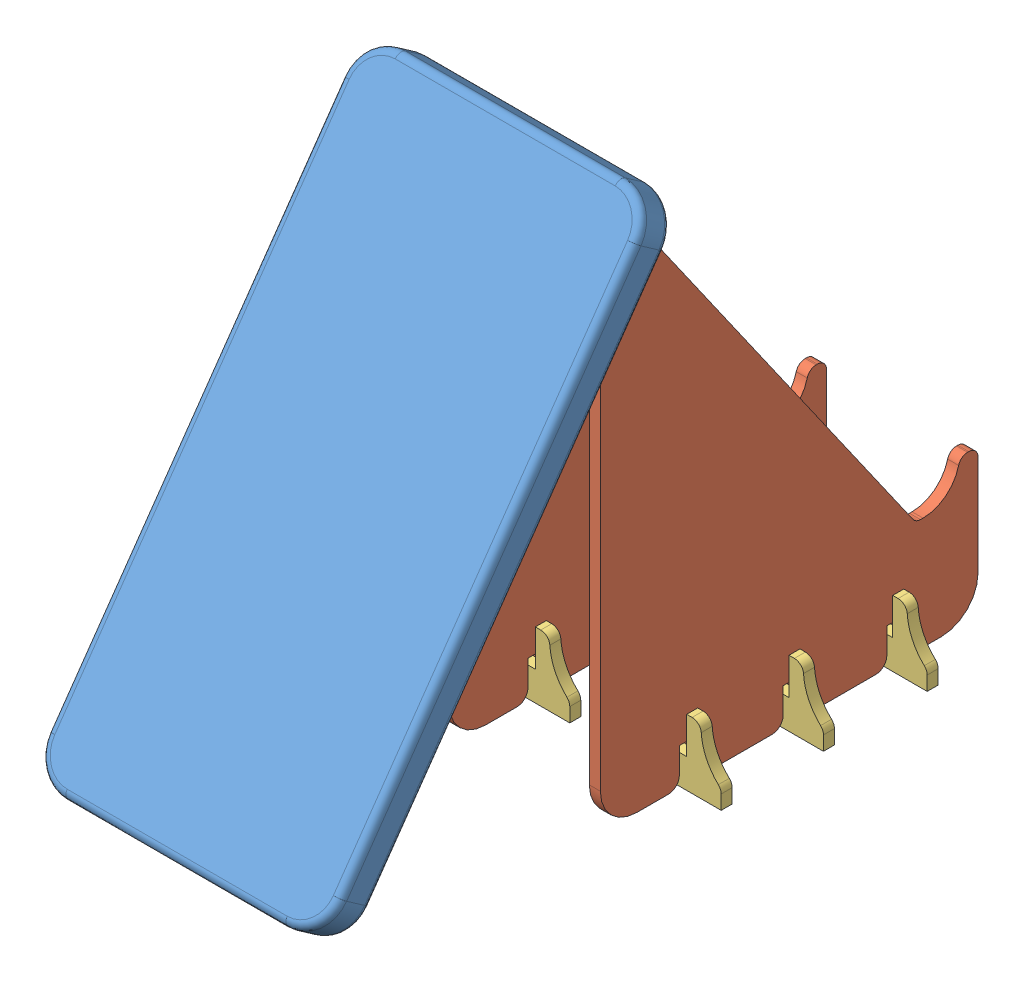
SolidWorks assembly paye mobile, configuration Default. Lengths in mm.
Overall size (80 162.83 199.81).
12 component instances, 5 part files, 35 mates.
Components (placement in the parent):
- iphone7plus-2: iphone7plus [Default] at (-40 -64.385 52.4393) x (-1 0 0) z (0 -0.573576 -0.819152) size (80 160 10)
- Part4-1: Part4 [Default] at origin
- Part5-1: Part5 [Default] at (0 -64.385 52.4393) x (0 -0.573576 -0.819152) z (1 0 0)
- Part6-1: Part6 [Default] x (0 0 -1) z (1 0 0) size (103.02 147.95 3) (hidden)
- Part6-2: Part6 [Default] at (-64.5031 0 0) x (0 0 -1) z (1 0 0) size (103.02 147.95 3)
- Part7-2: Part7 [Default] at (-64.2031 20 -48.3217) x (-1 0 0) z (0 0 -1) size (23.4 17.99 3)
- Part7-3: Part7 [Default] at (-64.2031 20 -76.6217) x (-1 0 0) z (0 0 -1) size (23.4 17.99 3)
- Part6-3: Part6 [Default] at (-23.2051 0 0) x (0 0 -1) z (1 0 0) size (103.02 147.95 3)
- Part7-4: Part7 [Default] at (-22.9051 20 -76.6217) x (-1 0 0) z (0 0 -1) size (23.4 17.99 3)
- Part7-5: Part7 [Default] at (-22.9051 20 -48.3217) x (-1 0 0) z (0 0 -1) size (23.4 17.99 3)
- Part7-6: Part7 [Default] at (-22.9051 20 -20.4254) x (-1 0 0) z (0 0 -1) size (23.4 17.99 3)
- Part7-7: Part7 [Default] at (-64.2031 20 -20.4254) x (-1 0 0) z (0 0 -1) size (23.4 17.99 3)
Mates (geometry in assembly coordinates):
- Angle2: planar angle = 0.610865 rad: plane of assembly through (0 0 0) normal (0 0 1); plane of assembly; plane of iphone7plus-2 through (-70 -121.7257 92.5897) normal (0 0.573576 0.819152)
- Coincident6: coincident: line of assembly; line of iphone7plus-2 through (-70 0 4.9149) axis (1 0 0); plane of assembly
- Coincident7: coincident: plane of assembly through (0 0 0) normal (1 0 0); plane of iphone7plus-2 through (0 -12.7801 4.0975) normal (1 0 0); plane of assembly
- Coincident8: coincident: line of assembly; line of iphone7plus-2 through (-10 -3.4415 0) axis (-1 0 0); plane of assembly
- InPlace2: in place: plane of iphone7plus-2 through (0 -12.7801 4.0975) normal (1 0 0); plane of Part6-1 through (0 0 0) normal (1 0 0); moOrthogonalPlaneRef_w of iphone7plus-2 through (0 -12.7801 4.0975) normal (1 0 0); plane of Part6-1 through (0 0 0) normal (0 1 0); plane of iphone7plus-2 through (0 -12.7801 4.0975) normal (1 0 0); plane of Part6-1 through (0 0 0) normal (0 0 -1); plane of iphone7plus-2 through (0 -12.7801 4.0975) normal (1 0 0); unknown of Part5-1
- Coincident9: coincident: plane of assembly; plane of assembly; plane of iphone7plus-2; plane of Part5-1
- Coincident10: coincident: plane of assembly; plane of assembly; moOrthogonalPlaneRef_w of iphone7plus-2 through (0 -64.385 52.4393) normal (0 0.819152 -0.573576); plane of Part5-1 through (0 -64.385 52.4393) normal (0 0.819152 -0.573576)
- Coincident11: coincident: plane of assembly; plane of assembly; moOrthogonalPlaneRef_w of iphone7plus-2 through (0 -64.385 52.4393) normal (0 0.573576 0.819152); plane of Part5-1 through (0 -64.385 52.4393) normal (0 -0.573576 -0.819152)
- InPlace3: in place: plane of Part6-1 through (0 0 0) normal (1 0 0); plane of Part6-1 through (0 0 0) normal (0 1 0); plane of Part6-1 through (0 0 0) normal (0 0 -1); unknown of Part6-1
- Coincident12: coincident: plane of assembly; plane of Part6-1; plane of assembly
- Coincident13: coincident: plane of assembly; plane of Part6-1 through (0 0 0) normal (0 1 0); moOrthogonalPlaneRef_w of assembly
- Coincident14: coincident: plane of assembly; plane of Part6-1 through (0 0 0) normal (0 0 -1); moOrthogonalPlaneRef_w of assembly
- Coincident16: coincident: plane of assembly; plane of assembly; plane of Part6-1 through (3 -151.6843 1.5402) normal (0 0 1); plane of Part6-2 through (-61.5031 -151.6843 1.5402) normal (0 0 1)
- Coincident17: coincident: line of assembly; plane of assembly; line of Part6-1 through (3 -161.6843 -8.4598) axis (0 0 -1); plane of Part6-2 through (-61.5031 -161.6843 -91.4835) normal (0 -1 0)
- Distance1: distance = 15.4969 mm: plane of assembly; plane of assembly; plane of iphone7plus-2 through (-80 -12.7801 4.0975) normal (-1 0 0); plane of Part6-2 through (-64.5031 -128.6793 -85.7977) normal (-1 0 0)
- Coincident22: coincident: plane of assembly; plane of assembly; plane of Part6-2 through (-61.5031 -161.6843 -48.3217) normal (0 0 -1); plane of Part7-2 through (-58.4355 -146.1943 -48.3217) normal (0 0 1)
- Coincident26: coincident: plane of assembly; plane of assembly; plane of Part7-2 through (-73.9031 -161.6843 -51.3217) normal (-1 0 0); plane of Part7-3 through (-73.9031 -161.6843 -79.6217) normal (-1 0 0)
- Coincident27: coincident: plane of assembly; plane of assembly; plane of Part7-2 through (-63.9031 -161.6843 -51.3217) normal (0 -1 0); plane of Part7-3 through (-63.9031 -161.6843 -79.6217) normal (0 -1 0)
- Coincident28: coincident: plane of assembly; plane of assembly; plane of Part6-2 through (-61.5031 -161.6843 -76.6217) normal (0 0 -1); plane of Part7-3 through (-58.4355 -146.1943 -76.6217) normal (0 0 1)
- Coincident29: coincident: plane of assembly; plane of assembly; plane of Part6-2 through (-61.5031 -124.1843 -101.4835) normal (0 0 -1); plane of Part6-3 through (-20.2051 -124.1843 -101.4835) normal (0 0 -1)
- Coincident30: coincident: plane of assembly; plane of assembly; plane of Part6-2 through (-61.5031 -161.6843 -91.4835) normal (0 -1 0); plane of Part6-3 through (-20.2051 -161.6843 -91.4835) normal (0 -1 0)
- Distance2: distance = 38.298 mm: plane of assembly; plane of assembly; plane of Part6-2 through (-61.5031 -128.6793 -85.7977) normal (1 0 0); plane of Part6-3 through (-23.2051 -128.6793 -85.7977) normal (-1 0 0)
- Coincident32: coincident: plane of assembly; plane of assembly; plane of Part7-3 through (-58.4355 -146.1943 -79.6217) normal (0 0 -1); plane of Part7-4 through (-17.1375 -146.1943 -79.6217) normal (0 0 -1)
- Coincident33: coincident: plane of assembly; plane of assembly; plane of Part7-3 through (-63.9031 -161.6843 -79.6217) normal (0 -1 0); plane of Part7-4 through (-22.6051 -161.6843 -79.6217) normal (0 -1 0)
- Coincident34: coincident: plane of assembly; plane of assembly; plane of Part6-3 through (-23.2051 -128.6793 -85.7977) normal (-1 0 0); plane of Part7-4 through (-23.2051 -143.6943 -79.6217) normal (1 0 0)
- Coincident35: coincident: plane of assembly; plane of assembly; plane of Part7-4 through (-22.6051 -161.6843 -79.6217) normal (0 -1 0); plane of Part7-5 through (-22.6051 -161.6843 -51.3217) normal (0 -1 0)
- Coincident36: coincident: plane of assembly; plane of assembly; plane of Part7-4 through (-9.2051 -161.6843 -79.6217) normal (1 0 0); plane of Part7-5 through (-9.2051 -161.6843 -51.3217) normal (1 0 0)
- Coincident37: coincident: plane of assembly; plane of assembly; plane of Part7-2 through (-58.4355 -146.1943 -51.3217) normal (0 0 -1); plane of Part7-5 through (-17.1375 -146.1943 -51.3217) normal (0 0 -1)
- Coincident39: coincident: plane of assembly; plane of assembly; plane of Part6-3 through (-20.2051 -161.6843 -91.4835) normal (0 -1 0); plane of Part7-6 through (-22.6051 -161.6843 -23.4254) normal (0 -1 0)
- Coincident41: coincident: plane of assembly; plane of assembly; plane of Part7-5 through (-9.2051 -161.6843 -51.3217) normal (1 0 0); plane of Part7-6 through (-9.2051 -161.6843 -23.4254) normal (1 0 0)
- Coincident42: coincident: plane of assembly; plane of assembly; plane of Part7-2 through (-73.9031 -161.6843 -51.3217) normal (-1 0 0); plane of Part7-7 through (-73.9031 -161.6843 -23.4254) normal (-1 0 0)
- Coincident43: coincident: plane of assembly; plane of assembly; plane of Part7-6 through (-22.6051 -161.6843 -23.4254) normal (0 -1 0); plane of Part7-7 through (-63.9031 -161.6843 -23.4254) normal (0 -1 0)
- Coincident44: coincident: plane of assembly; plane of assembly; plane of Part7-2 through (-63.9031 -161.6843 -51.3217) normal (0 -1 0); plane of Part7-7 through (-63.9031 -161.6843 -23.4254) normal (0 -1 0)
- Coincident45: coincident: plane of assembly; plane of assembly; plane of Part7-6 through (-17.1375 -146.1943 -23.4254) normal (0 0 -1); plane of Part7-7 through (-58.4355 -146.1943 -23.4254) normal (0 0 -1)
- Coincident46: coincident: plane of assembly; plane of assembly; plane of Part6-2 through (-64.5031 -128.6793 -85.7977) normal (-1 0 0); plane of Part7-3 through (-64.5031 -143.6943 -79.6217) normal (1 0 0)
